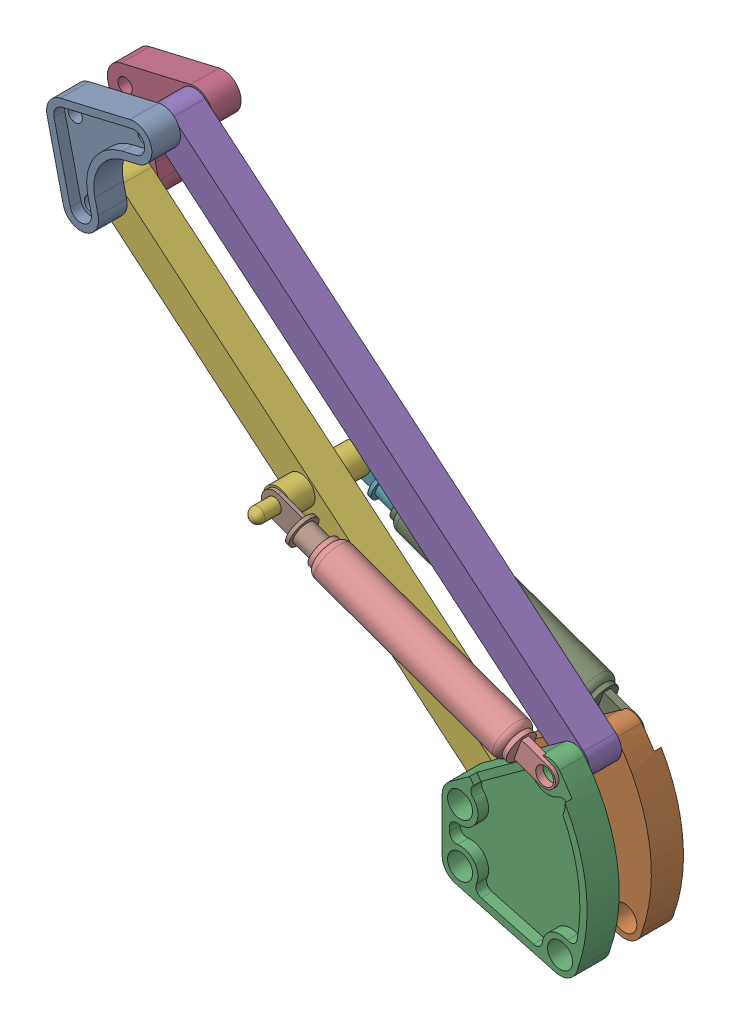
SolidWorks assembly Assem_middle, configuration Default. Lengths in mm.
Overall size (153.37 147.86 37).
11 component instances, 8 part files, 22 mates.
Components (placement in the parent):
- TopConnector-1: TopConnector [Default] at (-126.6227 104.8771 34.4362) x (0.227487 -0.973781 0) z (0 0 1) size (30 30 8)
- MiddleConnector-1: MiddleConnector [Default] at (3.276 31.3448 35.4362) size (40.57 49.23 9)
- MiddleConnectorMirrored-1: MiddleConnectorMirrored [Default] at (3.276 31.3448 34.4362) size (40.57 49.23 9)
- TopConnectorMirrored-1: TopConnectorMirrored [Default] at (-126.6227 104.8771 35.4362) x (0.227487 -0.973781 0) z (0 0 1) size (30 30 8)
- Leg-1: Leg [Default] at (-54.1915 80.7554 34.9362) x (0.766737 -0.641961 0) z (0.641961 0.766737 0) size (159 9 9)
- LegBrakedMiddle-1: LegBrakedMiddle [Default] at (-153.7788 25.842 34.9362) x (0.766044 -0.642788 0) z (0.642788 0.766044 0) size (149 37 9)
- Assem_springs-1: Assem_springs [Default] at (-31.9988 45.2287 23.4362) x (0.941668 -0.336542 0) z (0 0 1) size (87.54 10.06 33.06) (flexible)
  - Axel-1: Axel [Default] at (-3.1422 0 0) x (-1 0 0) z (0 -1 0) size (65.9 8 8)
  - Axel-2: Axel [Default] at (-3.1422 0 23) x (-1 0 0) z (0 -1 0) size (65.9 8 8)
  - Spring-1: Spring [Default] at origin size (70 10.06 10.06)
  - Spring-2: Spring [Default] at (0 0 23) size (70 10.06 10.06)
Mates (geometry in assembly coordinates):
- Concentric1: concentric anti-aligned: line of middle connector-1 through (3.3138 32.6084 23.4362) axis (0 0 1); cylinder of middle connector_mirrored-1 through (3.3138 32.6084 39.4362) axis (0 0 -1) radius 3
- Concentric2: concentric anti-aligned: line of middle connector-1 through (-19.3765 14.8868 21.4362) axis (0 0 1); cylinder of middle connector_mirrored-1 through (-19.3765 14.8868 39.4362) axis (0 0 -1) radius 3.5
- Concentric3: concentric: line of middle connector-1 through (-19.3765 -0.1132 21.4362) axis (0 0 1); cylinder of middle connector_mirrored-1 through (-19.3765 -0.1132 39.4362) axis (0 0 -1) radius 3.5
- Concentric4: concentric anti-aligned: line of middle connector-1 through (8.6354 -7.6189 21.4362) axis (0 0 1); cylinder of middle connector_mirrored-1 through (8.6354 -7.6189 39.4362) axis (0 0 -1) radius 3.5
- Concentric5: concentric: line of 3. topconn-1 through (-111.6968 128.9025 44.4362) axis (0 0 -1); cylinder of 3, topconn_mirrored-1 through (-111.6968 128.9025 30.4362) axis (0 0 1) radius 2
- Concentric6: concentric anti-aligned: line of 3. topconn-1 through (-131.1724 124.3527 44.4362) axis (0 0 -1); cylinder of 3, topconn_mirrored-1 through (-131.1724 124.3527 30.4362) axis (0 0 1) radius 2
- Concentric7: concentric anti-aligned: line of 3. topconn-1 through (-126.6227 104.8771 44.4362) axis (0 0 -1); cylinder of 3, topconn_mirrored-1 through (-126.6227 104.8771 30.4362) axis (0 0 1) radius 2
- Concentric10: concentric anti-aligned: cylinder of middle connector-1 through (3.3138 32.6084 30.4362) axis (0 0 1) radius 3; cylinder of 23. leg-1 through (3.3138 32.6084 39.4362) axis (0 0 -1) radius 2.5
- Coincident5: coincident anti-aligned: plane of middle connector-1 through (3.3138 32.6084 30.4362) normal (0 0 1); plane of 23. leg-1 through (3.3138 32.6084 30.4362) normal (0 0 -1)
- Concentric11: concentric anti-aligned: cylinder of 3, topconn_mirrored-1 through (-111.6968 128.9025 30.4362) axis (0 0 1) radius 2; cylinder of 23. leg-1 through (-111.6968 128.9025 39.4362) axis (0 0 -1) radius 2.5
- Coincident6: coincident anti-aligned: plane of 3. topconn-1 through (-111.6968 128.9025 39.4362) normal (0 0 -1); plane of 23. leg-1 through (3.3138 32.6084 39.4362) normal (0 0 1)
- Coincident7: coincident anti-aligned: plane of 3, topconn_mirrored-1 through (-111.6968 128.9025 30.4362) normal (0 0 1); plane of 23. leg-1 through (3.3138 32.6084 30.4362) normal (0 0 -1)
- Concentric12: concentric anti-aligned: cylinder of 3. middle connector-1 through (-19.3765 14.8868 30.4362) axis (0 0 1) radius 3.5; cylinder of 3. leg braked mid-1 through (-19.3765 14.8868 30.4362) axis (0 0 -1) radius 2.5
- Coincident8: coincident anti-aligned: plane of 3. middle connector-1 through (3.3138 32.6084 30.4362) normal (0 0 1); plane of 3. leg braked mid-1 through (-126.6227 104.8771 30.4362) normal (0 0 -1)
- Coincident9: coincident anti-aligned: plane of 3. middle connector_mirrored-1 through (3.3138 32.6084 39.4362) normal (0 0 -1); plane of 3. leg braked mid-1 through (-126.6227 104.8771 39.4362) normal (0 0 1)
- Concentric13: concentric aligned: cylinder of 3. topconn-1 through (-126.6227 104.8771 39.4362) axis (0 0 -1) radius 2; cylinder of 3. leg braked mid-1 through (-126.6227 104.8771 30.4362) axis (0 0 -1) radius 2.5
- Concentric14: concentric anti-aligned: cylinder of 3. leg braked mid-1 through (-72.9996 59.882 136.9582) axis (0 0 -1) radius 2; cylinder of Assem_springs-1/1. axel-1 through (-72.9996 59.882 23.9362) axis (0 0 1) radius 2.05
- Coincident10: coincident anti-aligned: plane of 3. leg braked mid-1 through (-72.9996 59.882 23.9362) normal (0 0 -1); plane of Assem_springs-1/1. axel-1 through (-72.9996 59.882 23.9362) normal (0 0 1)
- Coincident11: coincident anti-aligned: plane of 3. leg braked mid-1 through (-72.9996 59.882 45.9362) normal (0 0 1); plane of Assem_springs-1/1. axel-2 through (-72.9996 59.882 45.9362) normal (0 0 -1)
- Parallel1: parallel anti-aligned: cylinder of 3. middle connector-1 through (3.3138 32.6084 30.4362) axis (0 0 1) radius 3; cylinder of Assem_springs-1/1. spring-1 through (3.3138 32.6084 22.4362) axis (0 0 -1) radius 2.5
- Concentric17: concentric anti-aligned: cylinder of 3. middle connector-1 through (3.3138 32.6084 30.4362) axis (0 0 1) radius 3; cylinder of Assem_springs-1/1. spring-1 through (3.3138 32.6084 22.4362) axis (0 0 -1) radius 2.5
- Angle5: planar angle = 0.872665 rad aligned: plane of 3. middle connector-1 through (3.276 31.3448 35.4362) normal (1 0 0); plane of 3. leg braked mid-1 through (-123.7301 108.3243 39.4362) normal (0.642788 0.766044 0)
